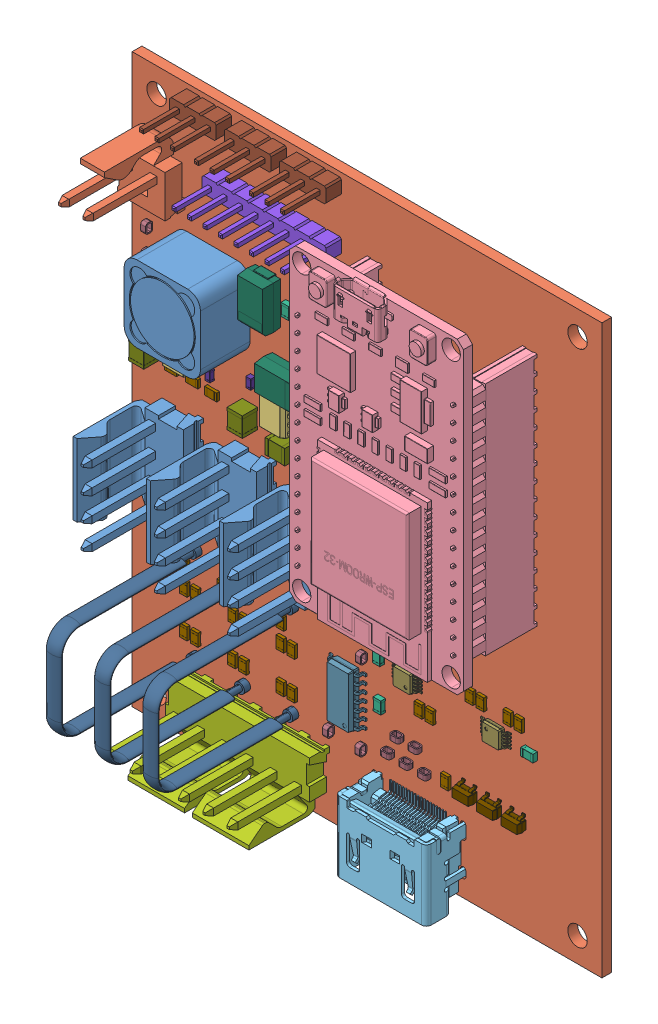
SolidWorks assembly ODMeter, configuration Default. Lengths in mm.
Overall size (77 94 27.4).
160 component instances, 20 part files, 0 mates.
Components (placement in the parent):
- ODMeter.step-1: ODMeter.step [Default] at origin size (77 94 27.4)
  - COIL.step-1: COIL.step [Default] at (-25.35 19.3 1.65) x (-1 0 0) z (0 0 1) size (12.5 12.5 8.17)
    - COMPOUND.step-1: COMPOUND.step [Default] at origin size (12.5 12.5 8.17)
  - 1718130002.step-1: 1718130002.step [Default] at (-33.65 33.6 1.65) size (7.79 10.01 17.02)
    - SOLID.step-1: SOLID.step [Default] at origin size (7.79 10.01 17.02)
  - HSOIC08.step-1: HSOIC08.step [Default] at (-13.75 8.15 1.65) x (0 -1 0) z (0 0 1) size (5 6.41 2.14)
    - COMPOUND-0.step-1: COMPOUND-0.step [Default] at origin size (5 6.41 2.14)
  - ESP-32.step-1: ESP-32.step [Default] at (14 17.51 1.65) x (-1 0 0) z (0 0 1) size (29.5 50.94 15.36)
    - COMPOUND-1.step-1: COMPOUND-1.step [Default] at origin size (29.5 50.94 15.36)
  - molex_0471510001.step-1: molex_0471510001.step [Default] at (8.5 -47.5 1.65) x (1 0 0) z (0 -1 0) size (15 8.38 12.15)
    - COMPOUND-2.step-1: COMPOUND-2.step [Default] at origin size (15 8.38 12.15)
  - C_0805.step-1: C_0805.step [Default] at (2.45 -25.5 1.65) x (0 -1 0) z (0 0 1) size (2 1.25 0.78)
    - SOLID-3.step-1: SOLID-3.step [Default] at origin size (2 1.25 0.78)
  - 026604060.step-1: 026604060.step [Default] at (-17.9 -41 1.65) x (-1 0 0) z (0 0 1) size (23.62 10.01 18.29)
    - SOLID-4.step-1: SOLID-4.step [Default] at origin size (23.62 10.01 18.29)
  - Pin_Header_Straight_1x08_Pitch2.54mm.step-1: Pin_Header_Straight_1x08_Pitch2.54mm.step [Default] at (-23.2 36.05 1.65) x (0 1 0) z (0 0 1) size (2.54 20.32 11.54)
    - SOLID-5.step-1: SOLID-5.step [Default] at origin size (2.54 20.32 11.54)
  - R_0805.step-1: R_0805.step [Default] at (-21.65 -24.95 1.65) x (0 1 0) z (0 0 1) size (2 1.25 0.5)
    - SOLID-6.step-1: SOLID-6.step [Default] at origin size (2 1.25 0.5)
  - R_0805.step-2: R_0805.step [Default] at (-23.45 -21.85 1.65) x (0 1 0) z (0 0 1) size (2 1.25 0.5)
    - SOLID-6.step-1: SOLID-6.step [Default] at origin size (2 1.25 0.5)
  - OART3.step-1: OART3.step [Default] at (-27.8 -26.4 1.65) x (0 1 0) z (0 0 1) size (16.89 2.5 27.02)
    - SOLID-7.step-1: SOLID-7.step [Default] at origin size (16.89 2.5 27.02)
  - C_0805.step-2: C_0805.step [Default] at (27 -20.225 1.65) x (-1 0 0) z (0 0 1) size (2 1.25 0.78)
    - SOLID-3.step-1: SOLID-3.step [Default] at origin size (2 1.25 0.78)
  - C_0805.step-3: C_0805.step [Default] at (-34.65 10.5 1.65) x (0 1 0) z (0 0 1) size (2 1.25 0.78)
    - SOLID-3.step-1: SOLID-3.step [Default] at origin size (2 1.25 0.78)
  - R_0805.step-3: R_0805.step [Default] at (-11.96 -24.95 1.65) x (0 1 0) z (0 0 1) size (2 1.25 0.5)
    - SOLID-6.step-1: SOLID-6.step [Default] at origin size (2 1.25 0.5)
  - R_0805.step-4: R_0805.step [Default] at (-11.96 -31.15 1.65) x (0 -1 0) z (0 0 1) size (2 1.25 0.5)
    - SOLID-6.step-1: SOLID-6.step [Default] at origin size (2 1.25 0.5)
  - R_0805.step-5: R_0805.step [Default] at (-13.75 -31.15 1.65) x (0 1 0) z (0 0 1) size (2 1.25 0.5)
    - SOLID-6.step-1: SOLID-6.step [Default] at origin size (2 1.25 0.5)
  - Pin_Header_Straight_1x03_Pitch2.54mm.step-1: Pin_Header_Straight_1x03_Pitch2.54mm.step [Default] at (-28.5 44.5 1.65) x (0 1 0) z (0 0 1) size (2.54 7.62 11.54)
    - SOLID-8.step-1: SOLID-8.step [Default] at origin size (2.54 7.62 11.54)
  - R_0805.step-6: R_0805.step [Default] at (-31.7 5.15 1.65) size (2 1.25 0.5)
    - SOLID-6.step-1: SOLID-6.step [Default] at origin size (2 1.25 0.5)
  - TSSOP-10_3x3mm_Pitch0.5mm.step-1: TSSOP-10_3x3mm_Pitch0.5mm.step [Default] at (21.25 -20.25 1.65) size (4.9 3 1)
    - SOLID-9.step-1: SOLID-9.step [Default] at origin size (4.9 3 1)
  - Harwin_S2761-46R.step-1: Harwin_S2761-46R.step [Default] at (7 -31.1 1.65) x (-1 0 0) z (0 0 1) size (1.6 0.8 1.15)
    - SOLID-10.step-1: SOLID-10.step [Default] at origin size (1.6 0.8 1.15)
  - SOIC-14_3.9x8.7mm_P1.27mm.step-1: SOIC-14_3.9x8.7mm_P1.27mm.step [Default] at (-3 -26.5 1.65) x (-1 0 0) z (0 0 1) size (6 8.7 1.75)
    - SOLID-11.step-1: SOLID-11.step [Default] at origin size (6 8.7 1.75)
  - R_0805.step-7: R_0805.step [Default] at (-29.6 -21.85 1.65) x (0 -1 0) z (0 0 1) size (2 1.25 0.5)
    - SOLID-6.step-1: SOLID-6.step [Default] at origin size (2 1.25 0.5)
  - R_0805.step-8: R_0805.step [Default] at (-31.4 -21.85 1.65) x (0 1 0) z (0 0 1) size (2 1.25 0.5)
    - SOLID-6.step-1: SOLID-6.step [Default] at origin size (2 1.25 0.5)
  - R_0805.step-9: R_0805.step [Default] at (-29.6 -24.95 1.65) x (0 1 0) z (0 0 1) size (2 1.25 0.5)
    - SOLID-6.step-1: SOLID-6.step [Default] at origin size (2 1.25 0.5)
  - R_0805.step-10: R_0805.step [Default] at (-27.8 -24.95 1.65) x (0 1 0) z (0 0 1) size (2 1.25 0.5)
    - SOLID-6.step-1: SOLID-6.step [Default] at origin size (2 1.25 0.5)
  - R_0805.step-11: R_0805.step [Default] at (-27.8 -31.15 1.65) x (0 -1 0) z (0 0 1) size (2 1.25 0.5)
    - SOLID-6.step-1: SOLID-6.step [Default] at origin size (2 1.25 0.5)
  - R_0805.step-12: R_0805.step [Default] at (-29.6 -31.15 1.65) x (0 1 0) z (0 0 1) size (2 1.25 0.5)
    - SOLID-6.step-1: SOLID-6.step [Default] at origin size (2 1.25 0.5)
  - R_0805.step-13: R_0805.step [Default] at (23.45 -16.875 1.65) x (0 1 0) z (0 0 1) size (2 1.25 0.5)
    - SOLID-6.step-1: SOLID-6.step [Default] at origin size (2 1.25 0.5)
  - R_0805.step-14: R_0805.step [Default] at (-21.65 -21.85 1.65) x (0 -1 0) z (0 0 1) size (2 1.25 0.5)
    - SOLID-6.step-1: SOLID-6.step [Default] at origin size (2 1.25 0.5)
  - R_0805.step-15: R_0805.step [Default] at (17.25 -16.9 1.65) x (0 1 0) z (0 0 1) size (2 1.25 0.5)
    - SOLID-6.step-1: SOLID-6.step [Default] at origin size (2 1.25 0.5)
  - R_0805.step-16: R_0805.step [Default] at (-19.85 -24.95 1.65) x (0 1 0) z (0 0 1) size (2 1.25 0.5)
    - SOLID-6.step-1: SOLID-6.step [Default] at origin size (2 1.25 0.5)
  - R_0805.step-17: R_0805.step [Default] at (-19.88 -31.15 1.65) x (0 -1 0) z (0 0 1) size (2 1.25 0.5)
    - SOLID-6.step-1: SOLID-6.step [Default] at origin size (2 1.25 0.5)
  - R_0805.step-18: R_0805.step [Default] at (-21.7 -31.15 1.65) x (0 1 0) z (0 0 1) size (2 1.25 0.5)
    - SOLID-6.step-1: SOLID-6.step [Default] at origin size (2 1.25 0.5)
  - R_0805.step-19: R_0805.step [Default] at (-15.55 -21.85 1.65) x (0 1 0) z (0 0 1) size (2 1.25 0.5)
    - SOLID-6.step-1: SOLID-6.step [Default] at origin size (2 1.25 0.5)
  - R_0805.step-20: R_0805.step [Default] at (-13.75 -24.95 1.65) x (0 1 0) z (0 0 1) size (2 1.25 0.5)
    - SOLID-6.step-1: SOLID-6.step [Default] at origin size (2 1.25 0.5)
  - C_0805.step-4: C_0805.step [Default] at (-25.1 10.6 1.65) x (0 -1 0) z (0 0 1) size (2 1.25 0.78)
    - SOLID-3.step-1: SOLID-3.step [Default] at origin size (2 1.25 0.78)
  - CP_Tantalum_Case-D_EIA-7343-31.step-1: CP_Tantalum_Case-D_EIA-7343-31.step [Default] at (-16.05 23.15 1.65) x (0 1 0) z (0 0 1) size (7.3 4.3 3.1)
    - SOLID-12.step-1: SOLID-12.step [Default] at origin size (7.3 4.3 3.1)
  - C_0805.step-5: C_0805.step [Default] at (-12.65 22.95 1.65) x (0 1 0) z (0 0 1) size (2 1.25 0.78)
    - SOLID-3.step-1: SOLID-3.step [Default] at origin size (2 1.25 0.78)
  - C_1210.step-1: C_1210.step [Default] at (-35.3 6.5 1.65) x (0 -1 0) z (0 0 1) size (3.2 2.5 2.5)
    - SOLID-13.step-1: SOLID-13.step [Default] at origin size (3.2 2.5 2.5)
  - C_1210.step-2: C_1210.step [Default] at (-19.15 4.75 1.65) x (0 1 0) z (0 0 1) size (3.2 2.5 2.5)
    - SOLID-13.step-1: SOLID-13.step [Default] at origin size (3.2 2.5 2.5)
  - C_1210.step-3: C_1210.step [Default] at (-8.25 5.75 1.65) x (0 1 0) z (0 0 1) size (3.2 2.5 2.5)
    - SOLID-13.step-1: SOLID-13.step [Default] at origin size (3.2 2.5 2.5)
  - CP_Tantalum_Case-D_EIA-7343-31.step-2: CP_Tantalum_Case-D_EIA-7343-31.step [Default] at (-11.9 13.4 1.65) x (-1 0 0) z (0 0 1) size (7.3 4.3 3.1)
    - SOLID-12.step-1: SOLID-12.step [Default] at origin size (7.3 4.3 3.1)
  - C_0603.step-1: C_0603.step [Default] at (-8.35 8.8 1.65) size (1.6 0.81 0.78)
    - SOLID-14.step-1: SOLID-14.step [Default] at origin size (1.6 0.81 0.78)
  - C_0603.step-2: C_0603.step [Default] at (-18.65 9.75 1.65) x (0 1 0) z (0 0 1) size (1.6 0.81 0.78)
    - SOLID-14.step-1: SOLID-14.step [Default] at origin size (1.6 0.81 0.78)
  - SOT-23.step-1: SOT-23.step [Default] at (16.85 -30.85 1.65) x (0 -1 0) z (0 0 1) size (2.8 2.9 1.55)
    - SOLID-15.step-1: SOLID-15.step [Default] at origin size (2.8 2.9 1.55)
  - SOT-23.step-2: SOT-23.step [Default] at (20.85 -30.85 1.65) x (0 -1 0) z (0 0 1) size (2.8 2.9 1.55)
    - SOLID-15.step-1: SOLID-15.step [Default] at origin size (2.8 2.9 1.55)
  - SOT-23.step-3: SOT-23.step [Default] at (24.85 -30.85 1.65) x (0 -1 0) z (0 0 1) size (2.8 2.9 1.55)
    - SOLID-15.step-1: SOLID-15.step [Default] at origin size (2.8 2.9 1.55)
  - R_0805.step-21: R_0805.step [Default] at (13.2 -31.05 1.65) x (0 -1 0) z (0 0 1) size (2 1.25 0.5)
    - SOLID-6.step-1: SOLID-6.step [Default] at origin size (2 1.25 0.5)
  - R_0805.step-22: R_0805.step [Default] at (-28.2 5.15 1.65) size (2 1.25 0.5)
    - SOLID-6.step-1: SOLID-6.step [Default] at origin size (2 1.25 0.5)
  - R_0805.step-23: R_0805.step [Default] at (8.9 -23 1.65) x (0 1 0) z (0 0 1) size (2 1.25 0.5)
    - SOLID-6.step-1: SOLID-6.step [Default] at origin size (2 1.25 0.5)
  - R_0805.step-24: R_0805.step [Default] at (-25.1 4.85 1.65) size (2 1.25 0.5)
    - SOLID-6.step-1: SOLID-6.step [Default] at origin size (2 1.25 0.5)
  - R_0805.step-25: R_0805.step [Default] at (10.7 -23 1.65) x (0 -1 0) z (0 0 1) size (2 1.25 0.5)
    - SOLID-6.step-1: SOLID-6.step [Default] at origin size (2 1.25 0.5)
  - HSOIC08.step-2: HSOIC08.step [Default] at (-29.95 8.85 1.65) x (0 1 0) z (0 0 1) size (5 6.41 2.14)
    - COMPOUND-0.step-1: COMPOUND-0.step [Default] at origin size (5 6.41 2.14)
  - C_0603.step-3: C_0603.step [Default] at (-25.35 7.45 1.65) x (0 -1 0) z (0 0 1) size (1.6 0.81 0.78)
    - SOLID-14.step-1: SOLID-14.step [Default] at origin size (1.6 0.81 0.78)
  - Harwin_S2761-46R.step-2: Harwin_S2761-46R.step [Default] at (0 -33.15 1.65) x (0 1 0) z (0 0 1) size (1.6 0.8 1.15)
    - SOLID-10.step-1: SOLID-10.step [Default] at origin size (1.6 0.8 1.15)
  - Harwin_S2761-46R.step-3: Harwin_S2761-46R.step [Default] at (10 -31.1 1.65) x (-1 0 0) z (0 0 1) size (1.6 0.8 1.15)
    - SOLID-10.step-1: SOLID-10.step [Default] at origin size (1.6 0.8 1.15)
  - Harwin_S2761-46R.step-4: Harwin_S2761-46R.step [Default] at (8.5 -28.9 1.65) size (1.6 0.8 1.15)
    - SOLID-10.step-1: SOLID-10.step [Default] at origin size (1.6 0.8 1.15)
  - 026604040.step-1: 026604040.step [Default] at (-31.88 -7.5 1.65) x (0 1 0) z (0 0 1) size (15.7 10.01 18.29)
    - SOLID-16.step-1: SOLID-16.step [Default] at origin size (15.7 10.01 18.29)
  - Harwin_S2761-46R.step-5: Harwin_S2761-46R.step [Default] at (5.5 -28.9 1.65) size (1.6 0.8 1.15)
    - SOLID-10.step-1: SOLID-10.step [Default] at origin size (1.6 0.8 1.15)
  - R_0805.step-26: R_0805.step [Default] at (19.05 -16.9 1.65) x (0 -1 0) z (0 0 1) size (2 1.25 0.5)
    - SOLID-6.step-1: SOLID-6.step [Default] at origin size (2 1.25 0.5)
  - OART3.step-2: OART3.step [Default] at (-19.88 -26.4 1.65) x (0 1 0) z (0 0 1) size (16.89 2.5 27.02)
    - SOLID-7.step-1: SOLID-7.step [Default] at origin size (16.89 2.5 27.02)
  - R_0805.step-27: R_0805.step [Default] at (-13.75 -21.85 1.65) x (0 -1 0) z (0 0 1) size (2 1.25 0.5)
    - SOLID-6.step-1: SOLID-6.step [Default] at origin size (2 1.25 0.5)
  - OART3.step-3: OART3.step [Default] at (-11.96 -26.4 1.65) x (0 1 0) z (0 0 1) size (16.89 2.5 27.02)
    - SOLID-7.step-1: SOLID-7.step [Default] at origin size (16.89 2.5 27.02)
  - TSSOP-10_3x3mm_Pitch0.5mm.step-2: TSSOP-10_3x3mm_Pitch0.5mm.step [Default] at (6.7 -19.65 1.65) x (-1 0 0) z (0 0 1) size (4.9 3 1)
    - SOLID-9.step-1: SOLID-9.step [Default] at origin size (4.9 3 1)
  - Harwin_S2761-46R.step-6: Harwin_S2761-46R.step [Default] at (-6.1 -33.15 1.65) x (0 -1 0) z (0 0 1) size (1.6 0.8 1.15)
    - SOLID-10.step-1: SOLID-10.step [Default] at origin size (1.6 0.8 1.15)
  - Harwin_S2761-46R.step-7: Harwin_S2761-46R.step [Default] at (4 -31.9 1.65) size (1.6 0.8 1.15)
    - SOLID-10.step-1: SOLID-10.step [Default] at origin size (1.6 0.8 1.15)
  - Harwin_S2761-46R.step-8: Harwin_S2761-46R.step [Default] at (-4.7 7.2 1.65) x (0 -1 0) z (0 0 1) size (1.6 0.8 1.15)
    - SOLID-10.step-1: SOLID-10.step [Default] at origin size (1.6 0.8 1.15)
  - C_1210.step-4: C_1210.step [Default] at (-12.55 3.95 1.65) size (3.2 2.5 2.5)
    - SOLID-13.step-1: SOLID-13.step [Default] at origin size (3.2 2.5 2.5)
  - C_0805.step-6: C_0805.step [Default] at (2.3 -18.7 1.65) x (0 -1 0) z (0 0 1) size (2 1.25 0.78)
    - SOLID-3.step-1: SOLID-3.step [Default] at origin size (2 1.25 0.78)
  - Pin_Header_Straight_1x03_Pitch2.54mm.step-2: Pin_Header_Straight_1x03_Pitch2.54mm.step [Default] at (-19.5 44.5 1.65) x (0 1 0) z (0 0 1) size (2.54 7.62 11.54)
    - SOLID-8.step-1: SOLID-8.step [Default] at origin size (2.54 7.62 11.54)
  - Harwin_S2761-46R.step-9: Harwin_S2761-46R.step [Default] at (0.1 -20.05 1.65) x (0 1 0) z (0 0 1) size (1.6 0.8 1.15)
    - SOLID-10.step-1: SOLID-10.step [Default] at origin size (1.6 0.8 1.15)
  - Pin_Header_Straight_1x03_Pitch2.54mm.step-3: Pin_Header_Straight_1x03_Pitch2.54mm.step [Default] at (-10.5 44.5 1.65) x (0 1 0) z (0 0 1) size (2.54 7.62 11.54)
    - SOLID-8.step-1: SOLID-8.step [Default] at origin size (2.54 7.62 11.54)
  - 026604040.step-2: 026604040.step [Default] at (-19.88 -7.5 1.65) x (0 1 0) z (0 0 1) size (15.7 10.01 18.29)
    - SOLID-16.step-1: SOLID-16.step [Default] at origin size (15.7 10.01 18.29)
  - 026604040.step-3: 026604040.step [Default] at (-7.88 -7.5 1.65) x (0 1 0) z (0 0 1) size (15.7 10.01 18.29)
    - SOLID-16.step-1: SOLID-16.step [Default] at origin size (15.7 10.01 18.29)
  - R_0805.step-28: R_0805.step [Default] at (25.25 -16.875 1.65) x (0 -1 0) z (0 0 1) size (2 1.25 0.5)
    - SOLID-6.step-1: SOLID-6.step [Default] at origin size (2 1.25 0.5)
  - Harwin_S2761-46R.step-10: Harwin_S2761-46R.step [Default] at (-35.9 15.5 1.65) x (0 -1 0) z (0 0 1) size (1.6 0.8 1.15)
    - SOLID-10.step-1: SOLID-10.step [Default] at origin size (1.6 0.8 1.15)
  - Harwin_S2761-46R.step-11: Harwin_S2761-46R.step [Default] at (-7.75 21.6 1.65) size (1.6 0.8 1.15)
    - SOLID-10.step-1: SOLID-10.step [Default] at origin size (1.6 0.8 1.15)
  - Harwin_S2761-46R.step-12: Harwin_S2761-46R.step [Default] at (-35.9 19.5 1.65) x (0 -1 0) z (0 0 1) size (1.6 0.8 1.15)
    - SOLID-10.step-1: SOLID-10.step [Default] at origin size (1.6 0.8 1.15)
  - Harwin_S2761-46R.step-13: Harwin_S2761-46R.step [Default] at (-35.9 23.5 1.65) x (0 -1 0) z (0 0 1) size (1.6 0.8 1.15)
    - SOLID-10.step-1: SOLID-10.step [Default] at origin size (1.6 0.8 1.15)
  - COMPOUND-17.step-1: COMPOUND-17.step [Default] at origin size (77 93 1.6)
